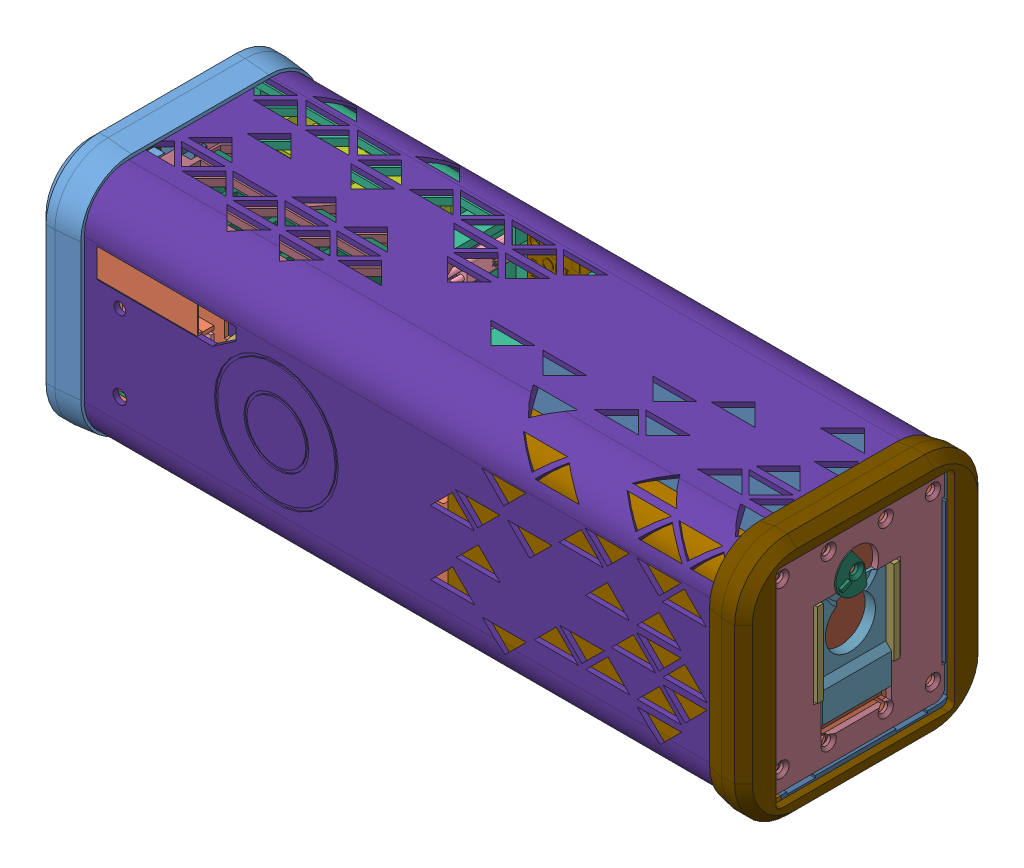
SolidWorks assembly Full Powerbank Assembly, configuration Default. Lengths in mm.
Overall size (243.88 83.1 83.1).
73 component instances, 40 part files, 193 mates.
Components (placement in the parent):
- Battery Holder base part-1: Battery Holder base part [Default] at (46.0757 75.848 60.5511) size (105.5 58.5 60)
- 18650 battery-1: 18650 battery [Default] at (37.7028 85.7801 99.4336) x (0 -1 0) z (0.549149 0 -0.835725) size (65 18 18)
- 18650 battery-2: 18650 battery [Default] at (74.8709 17.9159 53.2312) x (0 1 0) z (-0.546944 0 0.837169) size (65 18 18)
- 18650 battery-3: 18650 battery [Default] at (54.8709 17.9159 53.2312) x (0 1 0) z (-0.546944 0 0.837169) size (65 18 18)
- 18650 battery-4: 18650 battery [Default] at (34.8709 17.9159 53.2312) x (0 1 0) z (-0.546944 0 0.837169) size (65 18 18)
- 18650 battery-5: 18650 battery [Default] at (46.8938 85.7801 64.9021) x (0 -1 0) z (0 0 1) size (65 18 18)
- 18650 battery-6: 18650 battery [Default] at (82.8706 85.7801 62.4579) x (0 -1 0) z (-0.77356 0 0.633723) size (65 18 18)
- 18650 battery-7: 18650 battery [Default] at (86.8938 85.7801 64.9021) x (0 -1 0) z (0 0 1) size (65 18 18)
- 18650 battery-8: 18650 battery [Default] at (38.5972 85.7801 39.7291) x (0 -1 0) z (0.803541 0 0.595249) size (65 18 18)
- 18650 battery-9: 18650 battery [Default] at (86.8938 85.7801 24.9021) x (0 -1 0) z (0 0 1) size (65 18 18)
- 18650 battery-10: 18650 battery [Default] at (114.8709 17.9159 53.2312) x (0 1 0) z (-0.546944 0 0.837169) size (65 18 18)
- 18650 battery-11: 18650 battery [Default] at (6.8938 85.7801 24.9021) x (0 -1 0) z (0 0 1) size (65 18 18)
- 18650 battery-12: 18650 battery [Default] at (94.8709 17.9159 53.2312) x (0 1 0) z (-0.546944 0 0.837169) size (65 18 18)
- 18650 battery-13: 18650 battery [Default] at (26.8938 85.7801 24.9021) x (0 -1 0) z (0 0 1) size (65 18 18)
- 18650 battery-14: 18650 battery [Default] at (6.8938 85.7801 64.9021) x (0 -1 0) z (0 0 1) size (65 18 18)
- 18650 battery-15: 18650 battery [Default] at (66.8938 85.7801 24.9021) x (0 -1 0) z (0 0 1) size (65 18 18)
- Battery Holder Top Cap-2: Battery Holder Top Cap [Default] at (46.0757 27.848 60.5511) x (1 0 0) z (0 0 -1) size (119 13.21 60)
- Battery Holder Top Cap-3: Battery Holder Top Cap [Default] at (46.0757 27.848 60.5511) x (1 0 0) z (0 0 -1) size (119 13.21 60)
- 3s 25A BMS with balance-1: 3s 25A BMS with balance [Default] at (7.4633 51.471 58.769) x (0 -1 0) z (0 0 -1) size (56 3.6 45)
- XT60 male-2: XT60 male [Default] at (-1.7367 23.848 60.4011) x (0 0 1) z (-1 0 0) size (15.6 8 21.8)
- Electronics body-1: Electronics body [Default] at (-116.5367 53.3713 61.8287) x (0 0 1) z (0 1 0) size (63.75 130 74.25)
- 12V 150W inverter-1: 12V 150W inverter [Default] at (-62.0893 52.4138 28.0511) x (0 -1 0) z (-1 0 0) size (60 23.7 68)
- 20A relay-1: 20A relay [Default] at (-39.9404 68.2419 39.7511) x (0 1 0) z (-1 0 0) size (15.8 17.9 12.2)
- Step down converter Constant current-3: Step down converter Constant current [Default] at (-9.196 56.3158 28.5511) x (1 0 0) z (0 -1 0) size (26.3 16.25 62)
- 20A relay-2: 20A relay [Default] at (-34.6303 50.9419 39.7511) x (0 1 0) z (-1 0 0) size (15.8 17.9 12.2)
- 20A relay-3: 20A relay [Default] at (-34.6303 35.0419 39.7511) x (0 1 0) z (-1 0 0) size (15.8 17.9 12.2)
- DC Jack-1: DC Jack [Default] at (-116.5367 23.0836 36.7169) x (0 -1 0) z (0 0 1) size (9 15 15)
- USB C Female-1: USB C Female [Default] at (-108.5138 21.548 52.9665) x (0 0 1) z (-1 0 0) size (15 3.2 17.4)
- XT60 female-2: XT60 female [Default] at (-26.4367 23.848 60.2511) x (0 0 1) z (1 0 0) size (15.6 8 21.4)
- Electronics body mid layer-1: Electronics body mid layer [Default] at (-53.3688 57.1686 58.5511) x (1 0 0) z (0 -1 0) size (118 34.5 67.32)
- DC Jack-2: DC Jack [Default] at (-116.5367 78.5138 64.8993) x (0 0 1) z (0 1 0) size (9 15 15)
- Switch-2: Switch [Default] at (-110.0367 53.122 67.0755) x (0 0 1) z (0 -1 0) size (13 15.27 7)
- 200W boost converter 10A-4: 200W boost converter 10A [Default] at (-65.093 72.5468 63.0511) x (0 1 0) z (1 0 0) size (36.5 22.7 70)
- 20A relay-4: 20A relay [Default] at (-39.1428 41.3517 74.7511) x (1 0 0) z (0 1 0) size (15.8 17.9 12.2)
- 60x10mm fan-1: 60x10mm fan [Default] at (-62.9534 14.848 38.0511) size (60 10 60)
- Switch-3: Switch [Default] at (-110.0367 53.122 80.0755) x (0 0 1) z (0 -1 0) size (13 15.27 7)
- 12V to 5V USB-3: 12V to 5V USB [Default] at (-97.3792 41.0946 68.5511) x (0 -1 0) z (-1 0 0) size (28 15 58.9)
- Voltmeter and switch brcket-1: Voltmeter and switch brcket [Default] at (-110.5367 72.2443 73.8058) x (0 -1 0) z (0 0 -1) size (24.51 6 20.36)
- Voltmeter-2: Voltmeter [Default] at (-107.6767 73.0795 74.7637) x (0 -1 0) z (0 0 -1) size (22.8 8.96 10.5)
- Switch-4: Switch [Default] at (-110.0367 75.6225 88.1876) x (0 1 0) z (0 0 1) size (13 15.27 7)
- Electronics body top layer-4: Electronics body top layer [Default] at (13.4633 30.4962 89.1111) x (0 0 -1) z (0 1 0) size (14.91 130 73.98)
- Wireless charging coil-1: Wireless charging coil [Default] at (-43.0367 51.348 94.5511) x (0.923141 0.384463 0) z (0.384463 -0.923141 0) size (50 2.5 50)
- Wireless charging circuit-1: Wireless charging circuit [Default] at (-87.044 48.0841 93.5511) x (1 0 0) z (0 -1 0) size (30 2.5 32)
- Switch-6: Switch [Default] at (-110.0367 32.822 90.5755) x (0 0 1) z (0 -1 0) size (13 15.27 7)
- Switch-7: Switch [Default] at (-110.0367 25.822 90.5755) x (0 0 1) z (0 -1 0) size (13 15.27 7)
- AC Socket-2: AC Socket [Default] at (-119.5367 49.2567 56.8454) x (0 1 0) z (0 0 1) size (26.7 23.5 26.7)
- Adj bracket-2: Adj bracket [Default] at (-111.5367 61.6916 49.3943) x (0 1 0) z (0 0 1) size (26 10 6.2)
- Potencometer-2: Potencometer [Default] at (-109.2352 70.848 59.2044) x (-1 0 0) z (0 0 1) size (10 5 11.5)
- Adj Knob-1: Adj Knob [Default] at (-114.0367 68.148 56.9511) x (0.827198 -0.56191 0) z (0.56191 0.827198 0) size (25.5 4.9 16.38)
- Battery compartment base-1: Battery compartment base [Default] at (13.4633 48.4447 41.738) x (0 0 -1) z (0 -1 0) size (10.5 108.5 73.98)
- Battery compartment Top - Copy-1: Battery compartment Top - Copy [Default] at (13.4633 48.4447 41.738) x (0 0 -1) z (0 -1 0) size (63.5 108.3 74)
- Battery locking mechnism base-1: Battery locking mechnism base [Default] at (107.4633 55.2514 60.4566) x (0 0 1) z (0 1 0) size (60 5.5 69)
- Locking Shim-1: Locking Shim [Default] at (109.4633 53.6697 81.7455) x (0 0 -1) z (0 -1 0) size (25 6.1 28.5)
- Locking Shim-2: Locking Shim [Default] at (109.4633 50.0263 39.3567) x (0 0 1) z (0 1 0) size (25 6.1 28.5)
- Locking mechnism lid-1: Locking mechnism lid [Default] at (112.9633 51.742 60.2444) x (0 0 -1) z (0 -1 0) size (60 2 69)
- Pull Tab-1: Pull Tab [Default] at (109.4633 54.1884 58.8467) x (0 0 -1) z (0 -1 0) size (23.5 5.5 35.5)
- Rotate lock-1: Rotate lock [Default] at (112.9633 69.3177 62.7085) x (0 0.929004 0.37007) z (0 0.37007 -0.929004) size (14 3 9.86)
- Voltmeter-6: Voltmeter [Default] at (-107.6767 49.0795 88.9532) x (0 -1 0) z (0 0 -1) size (22.8 8.96 10.5)
- Switch-8: Switch [Default] at (-110.0367 60.322 40.0755) x (0 0 1) z (0 -1 0) size (13 15.27 7)
- IO shield-2: IO shield [Default] at (-116.5367 48.4447 41.738) x (0 0 -1) z (1 0 0) size (74 74 2.42)
- Outer sleeve-2: Outer sleeve [Default] at (-118.7367 53.1256 59.0279) x (0 1 0) z (1 0 0) size (78.6 78.6 234.7)
- Bottom Cap-1: Bottom Cap [Default] at (117.9633 58.0602 59.1604) x (0 1 0) z (0 0 1) size (82.6 12.5 82.6)
- Top Cap-1: Top Cap [Default] at (-120.7367 47.972 56.9587) x (0 -1 0) z (0 0 1) size (82.6 14 82.6)
- RGB controller cover-1: RGB controller cover [Default] at (-91.5447 69.6442 99.8511) x (1 0 0) z (0 1 0) size (34 1.65 9.5)
- AC Socket-3: AC Socket [Default] at (-118.7367 48.6742 56.9592) x (0 1 0) z (0 0 1) size (26.7 23.5 26.7)
- Inscription-1: Inscription [Default] at (78.4734 13.348 37.1232) x (1 0 0) z (0 0 -1) size (59.5 0.8 19.5)
- Temperature switch-1: Temperature switch [Default] at (-66.4617 65.07 90.1327) x (0 0 1) z (0 -1 0) size (7.5 3.65 24.95)
- Temperature switch-2: Temperature switch [Default] at (13.7133 34.6858 27.1511) x (0 -1 0) z (-1 0 0) size (7.5 3.65 24.95)
- Temperature switch-3: Temperature switch [Default] at (-36.5367 57.6858 44.8011) x (0 -1 0) z (0 0 1) size (7.5 3.65 24.95)
- Temperature switch-4: Temperature switch [Default] at (-74.9745 43.9916 68.5511) x (1 0 0) z (0 1 0) size (7.5 3.65 24.95)
- Temperature switch-5: Temperature switch [Default] at (-67.826 47.8234 58.5511) x (0 -1 0) z (1 0 0) size (7.5 3.65 24.95)
- Temperature switch-6: Temperature switch [Default] at (-79.935 28.848 59.2037) x (0 0 1) z (-1 0 0) size (7.5 3.65 24.95)
- Temperature switch-7: Temperature switch [Default] at (13.7133 68.5103 93.9511) x (0 1 0) z (-1 0 0) size (7.5 3.65 24.95)
Mates (geometry in assembly coordinates):
- Concentric1: concentric: cylinder of Battery Holder base part-1 through (17.4633 85.848 80.5511) axis (0 -1 0) radius 9.5; cylinder of 18650 battery-14 through (17.4633 91.7511 80.5511) axis (0 1 0) radius 9
- Coincident7: coincident: plane of Battery Holder base part-1 through (46.0757 84.348 60.5511) normal (0 -1 0); plane of 18650 battery-14 through (24.5633 84.348 80.5511) normal (0 1 0)
- Concentric2: concentric: cylinder of Battery Holder base part-1 through (37.4633 85.848 80.5511) axis (0 -1 0) radius 9.5; cylinder of 18650 battery-1 through (37.4633 91.7511 80.5511) axis (0 1 0) radius 9
- Coincident8: coincident: plane of Battery Holder base part-1 through (46.0757 84.348 60.5511) normal (0 -1 0); plane of 18650 battery-1 through (31.5296 84.348 76.6522) normal (0 1 0)
- Concentric3: concentric: cylinder of Battery Holder base part-1 through (57.4633 85.848 80.5511) axis (0 -1 0) radius 9.5; cylinder of 18650 battery-5 through (57.4633 91.7511 80.5511) axis (0 1 0) radius 9
- Coincident9: coincident: plane of Battery Holder base part-1 through (46.0757 84.348 60.5511) normal (0 -1 0); plane of 18650 battery-5 through (64.5633 84.348 80.5511) normal (0 1 0)
- Concentric4: concentric: cylinder of Battery Holder base part-1 through (77.4633 85.848 80.5511) axis (0 -1 0) radius 9.5; cylinder of 18650 battery-6 through (77.4633 91.7511 80.5511) axis (0 1 0) radius 9
- Coincident10: coincident: plane of Battery Holder base part-1 through (46.0757 84.348 60.5511) normal (0 -1 0); plane of 18650 battery-6 through (81.9627 84.348 86.0434) normal (0 1 0)
- Concentric5: concentric: cylinder of Battery Holder base part-1 through (97.4633 85.848 80.5511) axis (0 -1 0) radius 9.5; cylinder of 18650 battery-7 through (97.4633 91.7511 80.5511) axis (0 1 0) radius 9
- Coincident11: coincident: plane of Battery Holder base part-1 through (46.0757 84.348 60.5511) normal (0 -1 0); plane of 18650 battery-7 through (104.5633 84.348 80.5511) normal (0 1 0)
- Concentric6: concentric: cylinder of Battery Holder base part-1 through (17.4633 85.848 60.5511) axis (0 -1 0) radius 9.5; cylinder of 18650 battery-4 through (17.4633 11.9449 60.5511) axis (0 -1 0) radius 9
- Coincident12: coincident: plane of Battery Holder base part-1 through (46.0757 84.348 60.5511) normal (0 -1 0); plane of 18650 battery-4 through (9.9288 84.348 55.6286) normal (0 1 0)
- Concentric7: concentric: cylinder of Battery Holder base part-1 through (37.4633 85.848 60.5511) axis (0 -1 0) radius 9.5; cylinder of 18650 battery-3 through (37.4633 11.9449 60.5511) axis (0 -1 0) radius 9
- Coincident13: coincident: plane of Battery Holder base part-1 through (46.0757 84.348 60.5511) normal (0 -1 0); plane of 18650 battery-3 through (29.9288 84.348 55.6286) normal (0 1 0)
- Concentric8: concentric: cylinder of Battery Holder base part-1 through (57.4633 85.848 60.5511) axis (0 -1 0) radius 9.5; cylinder of 18650 battery-2 through (57.4633 11.9449 60.5511) axis (0 -1 0) radius 9
- Coincident14: coincident: plane of Battery Holder base part-1 through (46.0757 84.348 60.5511) normal (0 -1 0); plane of 18650 battery-2 through (49.9288 84.348 55.6286) normal (0 1 0)
- Concentric9: concentric: cylinder of Battery Holder base part-1 through (77.4633 85.848 60.5511) axis (0 -1 0) radius 9.5; cylinder of 18650 battery-12 through (77.4633 11.9449 60.5511) axis (0 -1 0) radius 9
- Coincident15: coincident: plane of Battery Holder base part-1 through (46.0757 84.348 60.5511) normal (0 -1 0); plane of 18650 battery-12 through (69.9288 84.348 55.6286) normal (0 1 0)
- Concentric10: concentric: cylinder of Battery Holder base part-1 through (97.4633 85.848 60.5511) axis (0 -1 0) radius 9.5; cylinder of 18650 battery-10 through (97.4633 11.9449 60.5511) axis (0 -1 0) radius 9
- Coincident16: coincident: plane of Battery Holder base part-1 through (46.0757 84.348 60.5511) normal (0 -1 0); plane of 18650 battery-10 through (89.9288 84.348 55.6286) normal (0 1 0)
- Concentric11: concentric: cylinder of Battery Holder base part-1 through (37.4633 85.848 40.5511) axis (0 -1 0) radius 9.5; cylinder of 18650 battery-13 through (37.4633 91.7511 40.5511) axis (0 1 0) radius 9
- Coincident17: coincident: plane of Battery Holder base part-1 through (46.0757 84.348 60.5511) normal (0 -1 0); plane of 18650 battery-13 through (44.5633 84.348 40.5511) normal (0 1 0)
- Concentric12: concentric: cylinder of Battery Holder base part-1 through (17.4633 85.848 40.5511) axis (0 -1 0) radius 9.5; cylinder of 18650 battery-11 through (17.4633 91.7511 40.5511) axis (0 1 0) radius 9
- Coincident18: coincident: plane of Battery Holder base part-1 through (46.0757 84.348 60.5511) normal (0 -1 0); plane of 18650 battery-11 through (24.5633 84.348 40.5511) normal (0 1 0)
- Concentric13: concentric: cylinder of Battery Holder base part-1 through (57.4633 85.848 40.5511) axis (0 -1 0) radius 9.5; cylinder of 18650 battery-8 through (57.4633 91.7511 40.5511) axis (0 1 0) radius 9
- Coincident19: coincident: plane of Battery Holder base part-1 through (46.0757 84.348 60.5511) normal (0 -1 0); plane of 18650 battery-8 through (61.6896 84.348 34.846) normal (0 1 0)
- Concentric14: concentric: cylinder of Battery Holder base part-1 through (77.4633 85.848 40.5511) axis (0 -1 0) radius 9.5; cylinder of 18650 battery-15 through (77.4633 91.7511 40.5511) axis (0 1 0) radius 9
- Coincident20: coincident: plane of Battery Holder base part-1 through (46.0757 84.348 60.5511) normal (0 -1 0); plane of 18650 battery-15 through (84.5633 84.348 40.5511) normal (0 1 0)
- Concentric15: concentric: cylinder of Battery Holder base part-1 through (97.4633 85.848 40.5511) axis (0 -1 0) radius 9.5; cylinder of 18650 battery-9 through (97.4633 91.7511 40.5511) axis (0 1 0) radius 9
- Coincident21: coincident: plane of Battery Holder base part-1 through (46.0757 84.348 60.5511) normal (0 -1 0); plane of 18650 battery-9 through (104.5633 84.348 40.5511) normal (0 1 0)
- Coincident22: coincident: plane of 18650 battery-4 through (11.5194 19.348 56.6678) normal (0 -1 0); plane of Battery Holder Top Cap-2 through (46.0757 19.348 60.5511) normal (0 1 0)
- Coincident23: coincident: plane of Battery Holder base part-1 through (46.0757 85.848 90.5511) normal (0 0 1); plane of Battery Holder Top Cap-2 through (46.0757 17.848 90.5511) normal (0 0 1)
- Coincident24: coincident: plane of Battery Holder base part-1 through (7.4633 85.848 60.5511) normal (-1 0 0); plane of Battery Holder Top Cap-2 through (7.4633 17.848 60.5511) normal (-1 0 0)
- Coincident25: coincident: plane of 18650 battery-4 through (11.5194 19.348 56.6678) normal (0 -1 0); plane of Battery Holder Top Cap-3 through (46.0757 19.348 60.5511) normal (0 1 0)
- Coincident26: coincident: plane of Battery Holder base part-1 through (46.0757 85.848 30.5511) normal (0 0 -1); plane of Battery Holder Top Cap-3 through (46.0757 17.848 30.5511) normal (0 0 -1)
- Coincident27: coincident: plane of Battery Holder base part-1 through (7.4633 85.848 60.5511) normal (-1 0 0); plane of Battery Holder Top Cap-3 through (7.4633 17.848 60.5511) normal (-1 0 0)
- Coincident28: coincident: plane of Battery Holder base part-1 through (7.4633 85.848 60.5511) normal (-1 0 0); plane of 3s 25A BMS with balance-1 through (7.4633 51.471 58.769) normal (1 0 0)
- Distance1: distance = 7 mm: plane of 3s 25A BMS with balance-1 through (6.2633 84.348 37.5511) normal (0 0 -1); plane of Battery Holder base part-1 through (46.0757 85.848 30.5511) normal (0 0 -1)
- Coincident37: coincident: plane of Battery Holder Top Cap-3 through (17.6713 17.348 52.6011) normal (0 0 1); plane of XT60 male-2 through (-1.7367 25.248 52.6011) normal (0 0 -1)
- Coincident38: coincident: plane of Battery Holder Top Cap-3 through (-9.5367 27.848 60.5511) normal (-1 0 0); plane of XT60 male-2 through (-9.5367 23.848 61.0461) normal (-1 0 0)
- Coincident39: coincident: plane of Battery Holder Top Cap-3 through (-2.5367 19.848 70.5511) normal (0 1 0); plane of XT60 male-2 through (-1.7367 19.848 55.6011) normal (0 -1 0)
- Coincident43: coincident: plane of Electronics body-1 through (-48.5367 24.848 61.8287) normal (0 1 0); plane of 12V 150W inverter-1 through (-48.5367 24.848 29.7511) normal (0 -1 0)
- Coincident44: coincident: plane of Electronics body-1 through (-48.5367 53.3713 28.0511) normal (0 0 1); plane of 12V 150W inverter-1 through (-62.0893 52.4138 28.0511) normal (0 0 -1)
- Coincident45: coincident: plane of Electronics body-1 through (-116.5367 77.848 34.5511) normal (-1 0 0); plane of 12V 150W inverter-1 through (-116.5367 84.848 29.7511) normal (-1 0 0)
- Coincident60: coincident: plane of Electronics body-1 through (-16.5367 25.348 26.0511) normal (0 0 1); plane of 20A relay-1 through (-39.9404 68.2419 26.0511) normal (0 0 -1)
- Coincident61: coincident: plane of Electronics body-1 through (-36.5367 53.3713 35.0511) normal (-1 0 0); plane of 20A relay-1 through (-36.5367 78.348 26.0511) normal (1 0 0)
- Coincident62: coincident: plane of Electronics body-1 through (-116.5367 78.348 35.0511) normal (0 -1 0); plane of 20A relay-1 through (-48.7367 78.348 26.0511) normal (0 1 0)
- Parallel11: parallel: plane of Battery Holder Top Cap-3 through (46.0757 17.848 30.5511) normal (0 0 -1); plane of Electronics body-1 through (-16.5367 25.348 26.0511) normal (0 0 1)
- Coincident70: coincident: plane of Electronics body-1 through (-3.2367 81.348 28.5511) normal (0 0 1); plane of Step down converter Constant current-3 through (-9.196 56.3158 28.5511) normal (0 0 -1)
- Concentric16: concentric: cylinder of Electronics body-1 through (-3.2367 81.348 10.0511) axis (0 0 1) radius 1.35; cylinder of Step down converter Constant current-3 through (-3.2367 81.348 30.1511) axis (0 0 -1) radius 1.675
- Concentric17: concentric: cylinder of Electronics body-1 through (-24.5367 24.348 10.0511) axis (0 0 1) radius 1.35; cylinder of Step down converter Constant current-3 through (-24.5367 24.348 30.1511) axis (0 0 -1) radius 1.675
- Coincident71: coincident: plane of Electronics body-1 through (-16.5367 25.348 26.0511) normal (0 0 1); plane of 20A relay-2 through (-34.6303 50.9419 26.0511) normal (0 0 -1)
- Coincident72: coincident: plane of Electronics body-1 through (-43.4266 61.048 72.8942) normal (1 0 0); plane of 20A relay-2 through (-43.4266 61.048 26.0511) normal (-1 0 0)
- Coincident73: coincident: plane of Electronics body-1 through (-116.5367 61.048 35.0511) normal (0 -1 0); plane of 20A relay-2 through (-43.4266 61.048 26.0511) normal (0 1 0)
- Coincident74: coincident: plane of Electronics body-1 through (-16.5367 25.348 26.0511) normal (0 0 1); plane of 20A relay-3 through (-34.6303 35.0419 26.0511) normal (0 0 -1)
- Coincident75: coincident: plane of Electronics body-1 through (-43.4266 61.048 72.8942) normal (1 0 0); plane of 20A relay-3 through (-43.4266 45.148 26.0511) normal (-1 0 0)
- Coincident76: coincident: plane of Electronics body-1 through (-43.4266 29.348 72.8942) normal (0 1 0); plane of 20A relay-3 through (-43.4266 29.348 26.0511) normal (0 -1 0)
- Coincident77: coincident: plane of Electronics body-1 through (-48.5367 53.3713 31.0511) normal (0 0 1); plane of DC Jack-1 through (-101.5367 26.9318 31.0511) normal (0 0 -1)
- Coincident78: coincident: plane of Electronics body-1 through (-102.5367 17.9318 31.0511) normal (0 1 0); plane of DC Jack-1 through (-101.5367 17.9318 31.0511) normal (0 -1 0)
- Coincident79: coincident: plane of Electronics body-1 through (-116.5367 77.848 34.5511) normal (-1 0 0); plane of DC Jack-1 through (-116.5367 23.0836 36.7169) normal (-1 0 0)
- Coincident80: coincident: plane of Electronics body-1 through (-108.0367 20.348 61.8287) normal (0 1 0); plane of USB C Female-1 through (-107.4367 20.348 50.0221) normal (0 -1 0)
- Coincident81: coincident: plane of Electronics body-1 through (-108.0367 53.3713 45.8338) normal (0 0 1); plane of USB C Female-1 through (-100.8367 22.348 45.8338) normal (0 0 -1)
- Coincident82: coincident: plane of Electronics body-1 through (-116.5367 77.848 34.5511) normal (-1 0 0); plane of USB C Female-1 through (-116.5367 22.348 45.8338) normal (-1 0 0)
- Coincident83: coincident: plane of Battery Holder base part-1 through (17.4633 86.348 60.5511) normal (0 1 0); plane of Electronics body-1 through (-16.5367 86.348 34.0511) normal (0 -1 0)
- Distance6: distance = 4.5 mm: plane of Battery Holder base part-1 through (46.0757 85.848 30.5511) normal (0 0 -1); plane of Electronics body-1 through (-16.5367 25.348 26.0511) normal (0 0 1)
- Coincident89: coincident: plane of Electronics body-1 through (-116.5367 27.348 52.4511) normal (0 0 1); plane of XT60 female-2 through (-26.4367 22.448 52.4511) normal (0 0 -1)
- Coincident91: coincident: plane of Electronics body-1 through (-116.5367 19.848 61.8287) normal (0 1 0); plane of XT60 female-2 through (-26.4367 19.848 68.0511) normal (0 -1 0)
- Coincident92: coincident: plane of Electronics body-1 through (-116.5367 27.348 52.4511) normal (0 0 1); plane of XT60 female-2 through (-26.4367 22.448 52.4511) normal (0 0 -1)
- Coincident93: coincident: plane of Electronics body-1 through (-10.0367 19.848 61.8287) normal (1 0 0); plane of XT60 female-2 through (-10.0367 23.848 60.8961) normal (1 0 0)
- Coincident99: coincident: plane of Electronics body-1 through (67.563 100.6452 58.5511) normal (0 0 1); plane of Electronics body mid layer-1 through (-53.3688 57.1686 58.5511) normal (0 0 -1)
- Coincident100: coincident: plane of Electronics body-1 through (-116.5367 77.848 34.5511) normal (-1 0 0); plane of Electronics body mid layer-1 through (-116.5367 88.848 61.0511) normal (-1 0 0)
- Coincident101: coincident: plane of Electronics body-1 through (-16.5367 88.848 34.5511) normal (0 1 0); plane of Electronics body mid layer-1 through (-116.5367 88.848 61.0511) normal (0 1 0)
- Coincident107: coincident: plane of Electronics body mid layer-1 through (-53.3688 57.1686 61.0511) normal (0 0 1); plane of DC Jack-2 through (-101.5367 72.848 61.0511) normal (0 0 -1)
- Coincident108: coincident: plane of Electronics body mid layer-1 through (-53.3688 72.848 71.0511) normal (0 1 0); plane of DC Jack-2 through (-101.5367 72.848 61.0511) normal (0 -1 0)
- Coincident109: coincident: plane of Electronics body mid layer-1 through (-116.5367 88.848 61.0511) normal (-1 0 0); plane of DC Jack-2 through (-116.5367 78.5138 64.8993) normal (-1 0 0)
- LimitDistance1: limit distance = 0.5 mm: plane of Battery Holder Top Cap-3 through (-9.5367 27.848 60.5511) normal (-1 0 0); plane of Electronics body-1 through (-10.0367 19.848 61.8287) normal (1 0 0)
- Coincident113: coincident: plane of Electronics body mid layer-1 through (-53.3688 57.1686 61.0511) normal (0 0 1); plane of Switch-2 through (-116.4367 58.548 61.0511) normal (0 0 -1)
- Coincident114: coincident: plane of Electronics body mid layer-1 through (-110.5367 51.648 59.908) normal (0 1 0); plane of Switch-2 through (-110.0367 51.648 67.0755) normal (0 -1 0)
- Coincident115: coincident: plane of Electronics body mid layer-1 through (-116.5367 88.848 61.0511) normal (-1 0 0); plane of Switch-2 through (-116.5367 53.122 67.0755) normal (-1 0 0)
- Coincident119: coincident: plane of Electronics body mid layer-1 through (-53.3688 57.1686 63.0511) normal (0 0 1); plane of 200W boost converter 10A-4 through (-65.093 72.5468 63.0511) normal (0 0 -1)
- Coincident120: coincident: plane of Electronics body mid layer-1 through (-29.0367 51.148 64.8511) normal (0 1 0); plane of 200W boost converter 10A-4 through (-99.5367 51.148 64.7511) normal (0 -1 0)
- Coincident122: coincident: plane of Electronics body mid layer-1 through (-53.3688 57.1686 61.0511) normal (0 0 1); plane of 20A relay-4 through (-39.1428 41.3517 61.0511) normal (0 0 -1)
- Coincident123: coincident: plane of Electronics body mid layer-1 through (-44.7367 37.948 69.0511) normal (0 1 0); plane of 20A relay-4 through (-29.0367 37.948 61.0511) normal (0 -1 0)
- Coincident124: coincident: plane of Electronics body mid layer-1 through (-29.0367 50.148 69.0511) normal (-1 0 0); plane of 20A relay-4 through (-29.0367 50.148 61.0511) normal (1 0 0)
- Coincident125: coincident: plane of Electronics body-1 through (-96.5367 37.848 91.0511) normal (1 0 0); plane of 60x10mm fan-1 through (-96.5367 24.848 31.0511) normal (-1 0 0)
- Coincident126: coincident: plane of Electronics body-1 through (-36.5367 37.848 31.0511) normal (0 0 1); plane of 60x10mm fan-1 through (-96.5367 24.848 31.0511) normal (0 0 -1)
- Coincident127: coincident: plane of Electronics body-1 through (-16.5367 14.848 34.5511) normal (0 -1 0); plane of 60x10mm fan-1 through (-62.9534 14.848 38.0511) normal (0 -1 0)
- Coincident128: coincident: plane of Switch-2 through (-116.4367 58.548 74.0511) normal (0 0 1); plane of Switch-3 through (-116.4367 58.548 74.0511) normal (0 0 -1)
- Coincident129: coincident: plane of Electronics body mid layer-1 through (-110.5367 51.648 59.908) normal (0 1 0); plane of Switch-3 through (-110.0367 51.648 80.0755) normal (0 -1 0)
- Coincident130: coincident: plane of Electronics body mid layer-1 through (-116.5367 88.848 61.0511) normal (-1 0 0); plane of Switch-3 through (-116.5367 53.122 80.0755) normal (-1 0 0)
- Coincident131: coincident: plane of Electronics body mid layer-1 through (-53.3688 57.1686 68.5511) normal (0 0 1); plane of 12V to 5V USB-3 through (-97.3792 41.0946 68.5511) normal (0 0 -1)
- Coincident132: coincident: plane of Electronics body mid layer-1 through (-105.511 53.2416 69.7511) normal (0 -1 0); plane of 12V to 5V USB-3 through (-97.3792 53.2416 69.5511) normal (0 1 0)
- Coincident133: coincident: plane of Electronics body-1 through (-116.5367 77.848 34.5511) normal (-1 0 0); plane of 12V to 5V USB-3 through (-116.5367 46.4916 64.5511) normal (-1 0 0)
- Coincident139: coincident: plane of Electronics body mid layer-1 through (-116.5367 88.848 61.0511) normal (-1 0 0); plane of Voltmeter and switch brcket-1 through (-116.5367 72.2443 73.8058) normal (-1 0 0)
- Coincident140: coincident: plane of Electronics body mid layer-1 through (-53.3688 63.848 71.0511) normal (0 -1 0); plane of Voltmeter and switch brcket-1 through (-116.5367 63.848 84.1616) normal (0 -1 0)
- Coincident141: coincident: plane of Voltmeter and switch brcket-1 through (-116.5367 87.848 72.6616) normal (0 0 1); plane of Voltmeter-2 through (-116.5367 87.148 72.6616) normal (0 0 -1)
- Coincident142: coincident: plane of Voltmeter and switch brcket-1 through (-116.5367 72.2443 73.8058) normal (-1 0 0); plane of Voltmeter-2 through (-116.5367 73.0795 74.7637) normal (-1 0 0)
- Coincident143: coincident: plane of Voltmeter and switch brcket-1 through (-116.5367 64.348 72.6616) normal (0 1 0); plane of Voltmeter-2 through (-116.5367 64.348 72.6616) normal (0 -1 0)
- Coincident144: coincident: plane of Voltmeter and switch brcket-1 through (-92.969 69.598 73.8058) normal (0 1 0); plane of Switch-4 through (-116.4367 69.598 82.7616) normal (0 -1 0)
- Coincident145: coincident: plane of Voltmeter and switch brcket-1 through (-92.969 72.2443 89.6616) normal (0 0 -1); plane of Switch-4 through (-110.0367 75.6225 89.6616) normal (0 0 1)
- Coincident146: coincident: plane of Voltmeter and switch brcket-1 through (-116.5367 72.2443 73.8058) normal (-1 0 0); plane of Switch-4 through (-116.5367 75.6225 88.1876) normal (-1 0 0)
- Coincident147: coincident: plane of Electronics body mid layer-1 through (-99.5367 88.848 63.0511) normal (-1 0 0); plane of 200W boost converter 10A-4 through (-99.5367 51.148 64.7511) normal (-1 0 0)
- Coincident156: coincident: circle of Electronics body-1; plane of Electronics body top layer-4 through (-116.5367 77.848 86.5511) normal (-1 0 0)
- Coincident157: coincident: plane of Electronics body-1 through (-116.5367 53.3713 87.0511) normal (0 0 1); plane of Electronics body top layer-4 through (13.4633 30.4962 87.0511) normal (0 0 -1)
- Coincident158: coincident: line of Electronics body-1 through (13.4633 14.8594 87.0511) axis (-1 0 0); line of Electronics body top layer-4 through (13.4633 14.8594 87.0511) axis (-1 0 0)
- Concentric18: concentric: cylinder of Electronics body top layer-4 through (-43.0367 51.348 94.5511) axis (0 0 -1) radius 25.5; cylinder of Wireless charging coil-1 through (-43.0367 51.348 95.5511) axis (0 0 -1) radius 25
- Coincident159: coincident: plane of Electronics body top layer-4 through (-43.0367 51.348 94.5511) normal (0 0 1); plane of Wireless charging coil-1 through (-43.0367 51.348 94.5511) normal (0 0 -1)
- Coincident160: coincident: plane of Electronics body top layer-4 through (-86.5367 30.4962 93.5511) normal (0 0 1); plane of Wireless charging circuit-1 through (-94.0367 37.348 93.5511) normal (0 0 -1)
- Coincident178: coincident: plane of Electronics body top layer-4 through (-110.5367 30.4962 84.5511) normal (0 0 1); plane of Switch-7 through (-116.4367 31.248 84.5511) normal (0 0 -1)
- Coincident179: coincident: plane of Electronics body top layer-4 through (-110.5367 24.348 89.1111) normal (0 1 0); plane of Switch-7 through (-110.0367 24.348 90.5755) normal (0 -1 0)
- Coincident180: coincident: plane of Electronics body top layer-4 through (-116.5367 77.848 86.5511) normal (-1 0 0); plane of Switch-7 through (-116.5367 25.822 90.5755) normal (-1 0 0)
- Coincident181: coincident: plane of Electronics body top layer-4 through (-110.5367 30.4962 84.5511) normal (0 0 1); plane of Switch-6 through (-116.4367 38.248 84.5511) normal (0 0 -1)
- Coincident183: coincident: plane of Electronics body top layer-4 through (-107.5367 38.348 89.1111) normal (0 -1 0); plane of Switch-6 through (-110.0367 38.348 90.5755) normal (0 1 0)
- Coincident184: coincident: plane of Electronics body top layer-4 through (-116.5367 77.848 86.5511) normal (-1 0 0); plane of Switch-6 through (-116.5367 32.822 90.5755) normal (-1 0 0)
- Distance16: distance = 3 mm: plane of Electronics body-1 through (-116.5367 77.848 34.5511) normal (-1 0 0); plane of AC Socket-2 through (-119.5367 49.2567 56.8454) normal (1 0 0)
- Coincident187: coincident: plane of Electronics body top layer-4 through (-97.1514 31.348 97.5511) normal (0 1 0); plane of Wireless charging circuit-1 through (-94.0367 31.348 94.5511) normal (0 -1 0)
- Coincident188: coincident: plane of Electronics body top layer-4 through (-70.0367 31.348 97.5511) normal (1 0 0); plane of Wireless charging circuit-1 through (-70.0367 63.348 94.5511) normal (1 0 0)
- Coincident192: coincident: plane of Electronics body mid layer-1 through (-116.5367 88.848 61.0511) normal (-1 0 0); plane of Adj bracket-2 through (-116.5367 61.6916 49.3943) normal (-1 0 0)
- Coincident195: coincident: plane of Electronics body mid layer-1 through (-104.5367 57.1686 58.5511) normal (-1 0 0); plane of Potencometer-2 through (-104.5367 65.848 58.5511) normal (1 0 0)
- Coincident196: coincident: plane of Electronics body mid layer-1 through (-53.3688 65.848 71.0511) normal (0 1 0); plane of Potencometer-2 through (-109.2352 65.848 59.2044) normal (0 -1 0)
- Coincident197: coincident: plane of Electronics body mid layer-1 through (-53.3688 57.1686 58.5511) normal (0 0 -1); plane of Potencometer-2 through (-104.5367 65.848 58.5511) normal (0 0 -1)
- Concentric20: concentric: cylinder of Adj bracket-2 through (-114.0367 68.148 49.5511) axis (0 0 1) radius 1.45; cylinder of Adj Knob-1 through (-114.0367 68.148 52.0511) axis (0 0 1) radius 1.25
- Coincident198: coincident: plane of Adj bracket-2 through (-116.5367 61.6916 54.5511) normal (0 0 1); plane of Adj Knob-1 through (-114.0367 68.148 54.5511) normal (0 0 -1)
- Distance9: distance = 1.2 mm: plane of Adj bracket-2 through (-111.5367 81.148 58.5511) normal (0 1 0); plane of Electronics body mid layer-1 through (-116.5367 82.348 52.5511) normal (0 -1 0)
- Coincident202: coincident: plane of Electronics body-1 through (-16.5367 25.848 23.5511) normal (0 0 -1); plane of Battery compartment Top - Copy-1 through (133.4633 48.4447 23.5511) normal (0 0 -1)
- Coincident203: coincident: plane of Electronics body-1 through (-16.5367 14.848 34.5511) normal (0 -1 0); plane of Battery compartment Top - Copy-1 through (133.4633 14.848 41.738) normal (0 -1 0)
- Coincident204: coincident: plane of Electronics body-1 through (13.4633 25.348 87.0511) normal (1 0 0); plane of Battery compartment Top - Copy-1 through (13.4633 48.4447 41.738) normal (-1 0 0)
- Coincident205: coincident: plane of Battery compartment base-1 through (265.4633 -1.8965 87.0511) normal (0 0 -1); plane of Battery compartment Top - Copy-1 through (133.4633 48.4447 87.0511) normal (0 0 1)
- Coincident206: coincident: line of Battery compartment base-1 through (13.4633 14.8594 87.0511) axis (1 0 0); line of Battery compartment Top - Copy-1 through (115.7633 14.8594 87.0511) axis (-1 0 0)
- Coincident207: coincident: plane of Electronics body top layer-4 through (13.4633 77.848 86.5511) normal (1 0 0); plane of Battery compartment base-1 through (13.4633 48.4447 41.738) normal (-1 0 0)
- Coincident209: coincident: plane of Battery Holder base part-1 through (46.0757 85.848 30.5511) normal (0 0 -1); plane of Battery locking mechnism base-1 through (109.4633 55.2514 30.5511) normal (0 0 -1)
- Coincident210: coincident: plane of Battery Holder base part-1 through (17.4633 86.348 60.5511) normal (0 1 0); plane of Battery locking mechnism base-1 through (109.4633 86.348 60.4566) normal (0 1 0)
- Coincident212: coincident: plane of Battery locking mechnism base-1 through (112.9633 66.348 60.4566) normal (0 -1 0); plane of Locking Shim-1 through (112.7633 66.348 97.5511) normal (0 1 0)
- Coincident214: coincident: plane of Battery locking mechnism base-1 through (112.9633 37.348 60.4566) normal (0 1 0); plane of Locking Shim-2 through (112.7633 37.348 23.5511) normal (0 -1 0)
- Coincident215: coincident: plane of Battery compartment Top - Copy-1 through (133.4633 48.4447 23.5511) normal (0 0 -1); plane of Locking Shim-2 through (112.7633 37.348 23.5511) normal (0 0 -1)
- Coincident216: coincident: plane of Battery compartment base-1 through (133.4633 48.4447 97.5511) normal (0 0 1); plane of Locking Shim-1 through (112.7633 66.348 97.5511) normal (0 0 1)
- Coincident217: coincident: plane of Battery locking mechnism base-1 through (112.9633 55.2514 60.4566) normal (1 0 0); plane of Locking mechnism lid-1 through (112.9633 51.742 60.2444) normal (-1 0 0)
- Coincident218: coincident: plane of Battery locking mechnism base-1 through (97.9633 27.348 31.5511) normal (0 0 -1); plane of Locking mechnism lid-1 through (114.9633 51.742 31.5511) normal (0 0 -1)
- Coincident219: coincident: plane of Battery locking mechnism base-1 through (109.4633 86.348 60.4566) normal (0 1 0); plane of Locking mechnism lid-1 through (114.9633 86.348 60.2444) normal (0 1 0)
- Coincident220: coincident: plane of Battery locking mechnism base-1 through (109.4633 55.2514 60.4566) normal (1 0 0); plane of Pull Tab-1 through (109.4633 54.1884 58.8467) normal (-1 0 0)
- Coincident221: coincident: plane of Battery locking mechnism base-1 through (112.9633 37.348 60.4566) normal (0 1 0); plane of Pull Tab-1 through (112.9633 37.348 72.0511) normal (0 -1 0)
- Coincident222: coincident: plane of Locking Shim-2 through (112.7633 37.348 48.5511) normal (0 0 1); plane of Pull Tab-1 through (112.9633 65.348 48.5511) normal (0 0 -1)
- Concentric21: concentric: cylinder of Battery locking mechnism base-1 through (109.9633 69.348 60.4566) axis (1 0 0) radius 1.35; cylinder of Rotate lock-1 through (114.9633 69.348 60.4566) axis (-1 0 0) radius 1.5
- Coincident223: coincident: plane of Battery locking mechnism base-1 through (112.9633 55.2514 60.4566) normal (1 0 0); plane of Rotate lock-1 through (112.9633 69.348 60.4566) normal (-1 0 0)
- Coincident225: coincident: plane of Electronics body top layer-4 through (-105.5367 40.348 86.8511) normal (0 0 1); plane of Voltmeter-6 through (-116.5367 63.148 86.8511) normal (0 0 -1)
- Coincident226: coincident: plane of Electronics body top layer-4 through (-107.5367 40.348 89.1111) normal (0 1 0); plane of Voltmeter-6 through (-116.5367 40.348 86.8511) normal (0 -1 0)
- Coincident227: coincident: plane of Electronics body top layer-4 through (-116.5367 77.848 86.5511) normal (-1 0 0); plane of Voltmeter-6 through (-116.5367 49.0795 88.9532) normal (-1 0 0)
- Coincident229: coincident: plane of Electronics body mid layer-1 through (-116.5367 88.848 61.0511) normal (-1 0 0); plane of Switch-8 through (-116.5367 60.322 40.0755) normal (-1 0 0)
- Distance11: distance = 8 mm: plane of Switch-8 through (-116.4367 65.748 34.0511) normal (0 0 -1); plane of Electronics body-1 through (-16.5367 25.348 26.0511) normal (0 0 1)
- Coincident234: coincident: plane of Electronics body top layer-4 through (-107.5367 30.4962 97.5511) normal (0 0 1); plane of IO shield-2 through (-118.7367 48.4447 97.5511) normal (0 0 1)
- Coincident235: coincident: plane of Electronics body-1 through (-16.5367 88.848 34.5511) normal (0 1 0); plane of IO shield-2 through (-118.7367 88.848 34.5511) normal (0 1 0)
- Distance12: distance = 0 mm: plane of Electronics body mid layer-1 through (-116.5367 88.848 61.0511) normal (-1 0 0); plane of IO shield-2 through (-116.5367 48.4447 41.738) normal (1 0 0)
- Coincident241: coincident: plane of IO shield-2 through (-118.7367 48.4447 41.738) normal (-1 0 0); plane of Outer sleeve-2 through (-118.7367 53.1256 59.0279) normal (-1 0 0)
- Coincident242: coincident: plane of Electronics body mid layer-1 through (-53.3688 57.1686 71.0511) normal (0 0 1); plane of Voltmeter and switch brcket-1 through (-116.5367 88.348 71.0511) normal (0 0 -1)
- Coincident243: coincident: plane of Battery compartment base-1 through (115.9633 106.0044 -5.4489) normal (1 0 0); plane of Bottom Cap-1 through (115.9633 58.0602 59.1604) normal (-1 0 0)
- Coincident246: coincident: plane of Outer sleeve-2 through (-118.7367 53.1256 59.0279) normal (-1 0 0); plane of Top Cap-1 through (-118.7367 47.972 56.9587) normal (1 0 0)
- Coincident247: coincident: plane of Outer sleeve-2 through (115.9633 91.148 59.0279) normal (0 1 0); plane of Top Cap-1 through (-110.7367 91.148 56.9587) normal (0 -1 0)
- Coincident248: coincident: plane of Outer sleeve-2 through (115.9633 53.1256 99.8511) normal (0 0 1); plane of Top Cap-1 through (-110.7367 47.972 99.8511) normal (0 0 -1)
- Distance17: distance = 0.6 mm: plane of Battery compartment base-1 through (133.4633 48.4447 97.5511) normal (0 0 1); plane of Outer sleeve-2 through (-172.0367 25.248 98.1511) normal (0 0 -1)
- Distance18: distance = 0.6 mm: plane of Outer sleeve-2 through (-172.0367 89.448 87.1511) normal (0 -1 0); plane of Battery compartment Top - Copy-1 through (133.4633 88.848 41.738) normal (0 1 0)
- Coincident249: coincident: plane of Outer sleeve-2 through (115.9633 53.1256 99.8511) normal (0 0 1); plane of RGB controller cover-1 through (-91.5447 69.6442 99.8511) normal (0 0 1)
- Coincident250: coincident: plane of Outer sleeve-2 through (-103.4017 75.4104 89.8511) normal (0 -1 0); plane of RGB controller cover-1 through (-103.4017 75.4104 99.4011) normal (0 1 0)
- Coincident251: coincident: plane of Outer sleeve-2 through (-103.4017 75.4104 89.8511) normal (1 0 0); plane of RGB controller cover-1 through (-103.4017 75.4104 99.4011) normal (-1 0 0)
- Coincident252: coincident: plane of Outer sleeve-2 through (115.9633 12.548 59.0279) normal (0 -1 0); plane of Bottom Cap-1 through (227.1205 12.548 37.2511) normal (0 1 0)
- Coincident253: coincident: plane of Outer sleeve-2 through (115.9633 53.1256 99.8511) normal (0 0 1); plane of Bottom Cap-1 through (227.1205 27.548 99.8511) normal (0 0 -1)
- Coincident254: coincident: plane of IO shield-2 through (-108.7367 35.8328 54.0522) normal (0 1 0); plane of AC Socket-3 through (-98.7367 35.8328 53.9592) normal (0 -1 0)
- Coincident255: coincident: plane of IO shield-2 through (-118.7367 48.4447 41.738) normal (-1 0 0); plane of AC Socket-3 through (-118.7367 48.6742 56.9592) normal (1 0 0)
- Coincident256: coincident: plane of IO shield-2 through (-108.7367 40.0057 32.7592) normal (0 0 1); plane of AC Socket-3 through (-98.7367 39.6768 32.7592) normal (0 0 -1)
- Coincident257: coincident: plane of 12V 150W inverter-1 through (-103.0367 65.848 44.7511) normal (0 -1 0); plane of Switch-8 through (-110.0367 65.848 40.0755) normal (0 1 0)
- Coincident258: coincident: plane of Outer sleeve-2 through (-118.7367 13.348 59.0279) normal (0 -1 0); plane of Inscription-1 through (78.4734 13.348 37.1232) normal (0 1 0)
- Coincident259: coincident: plane of Outer sleeve-2 through (46.8592 13.348 37.7714) normal (0 0 1); plane of Inscription-1 through (47.3592 12.548 37.7714) normal (0 0 -1)
- Coincident260: coincident: plane of Outer sleeve-2 through (106.8592 13.348 57.7714) normal (-1 0 0); plane of Inscription-1 through (106.8592 12.548 37.7714) normal (1 0 0)
- Coincident261: coincident: plane of 12V to 5V USB-3 through (-97.3792 41.0946 68.5511) normal (0 0 -1); plane of Temperature switch-4 through (-74.9745 43.9916 68.5511) normal (0 0 1)
- Coincident262: coincident: plane of 12V to 5V USB-3 through (-97.3792 25.2416 69.5511) normal (0 -1 0); plane of Temperature switch-4 through (-88.1367 25.2416 64.9011) normal (0 -1 0)
- Coincident263: coincident: line of 12V to 5V USB-3 through (-95.6367 25.2416 69.5511) axis (0 0 -1); plane of Temperature switch-4 through (-95.6367 43.9916 64.9011) normal (-1 0 0)
- Coincident264: coincident: plane of 12V 150W inverter-1 through (-62.0893 28.848 28.0511) normal (0 1 0); plane of Temperature switch-6 through (-79.935 28.848 59.2037) normal (0 -1 0)
- Coincident267: coincident: plane of 12V 150W inverter-1 through (-61.185 28.848 46.0415) normal (1 0 0); plane of Temperature switch-6 through (-61.185 32.498 46.0415) normal (1 0 0)
- Coincident268: coincident: plane of 12V 150W inverter-1 through (-70.2839 28.848 46.0415) normal (0 0 1); plane of Temperature switch-6 through (-79.935 32.498 46.0415) normal (0 0 1)
- Coincident269: coincident: plane of Electronics body mid layer-1 through (-53.3688 57.1686 58.5511) normal (0 0 -1); plane of Temperature switch-5 through (-67.826 47.8234 58.5511) normal (0 0 1)
- Coincident270: coincident: plane of Electronics body mid layer-1 through (-88.5279 60.9856 54.2511) normal (0 1 0); plane of Temperature switch-5 through (-67.826 60.9856 54.9011) normal (0 -1 0)
- Coincident271: coincident: plane of Electronics body mid layer-1 through (-86.576 58.9856 70.3142) normal (1 0 0); plane of Temperature switch-5 through (-86.576 60.9856 54.9011) normal (-1 0 0)
- Coincident272: coincident: plane of 200W boost converter 10A-4 through (-66.4617 93.07 87.3416) normal (-1 0 0); plane of Temperature switch-1 through (-66.4617 65.07 90.1327) normal (1 0 0)
- Coincident273: coincident: plane of 200W boost converter 10A-4 through (-70.8864 93.07 69.4705) normal (0 0 1); plane of Temperature switch-1 through (-70.1117 65.07 69.4705) normal (0 0 -1)
- Coincident274: coincident: plane of 200W boost converter 10A-4 through (-88.4522 65.07 81.7511) normal (0 -1 0); plane of Temperature switch-1 through (-70.1117 65.07 76.9705) normal (0 -1 0)
- Coincident275: coincident: plane of Battery compartment base-1 through (13.4633 48.4447 93.9511) normal (0 0 -1); plane of Temperature switch-7 through (13.7133 68.5103 93.9511) normal (0 0 1)
- Coincident276: coincident: plane of Battery compartment base-1 through (32.4633 47.848 93.9511) normal (0 1 0); plane of Temperature switch-7 through (13.7133 47.848 90.3011) normal (0 -1 0)
- Coincident277: coincident: plane of Battery compartment base-1 through (32.4633 47.848 93.9511) normal (-1 0 0); plane of Temperature switch-7 through (32.4633 55.348 90.3011) normal (1 0 0)
- Coincident278: coincident: plane of Battery compartment Top - Copy-1 through (32.4633 55.848 27.1511) normal (-1 0 0); plane of Temperature switch-2 through (32.4633 47.848 30.8011) normal (1 0 0)
- Coincident279: coincident: plane of Battery compartment Top - Copy-1 through (13.4633 48.4447 27.1511) normal (0 0 1); plane of Temperature switch-2 through (13.7133 34.6858 27.1511) normal (0 0 -1)
- Coincident280: coincident: plane of Battery compartment Top - Copy-1 through (32.4633 47.848 27.1511) normal (0 1 0); plane of Temperature switch-2 through (13.7133 47.848 30.8011) normal (0 -1 0)
- Coincident281: coincident: plane of 20A relay-1 through (-36.5367 78.348 26.0511) normal (1 0 0); plane of Temperature switch-3 through (-36.5367 57.6858 44.8011) normal (-1 0 0)
- Coincident282: coincident: plane of 20A relay-1 through (-48.7367 78.348 26.0511) normal (0 1 0); plane of Temperature switch-3 through (-32.8867 78.348 44.8011) normal (0 1 0)
- Coincident283: coincident: plane of 20A relay-1 through (-39.9404 68.2419 26.0511) normal (0 0 -1); plane of Temperature switch-3 through (-32.8867 70.848 26.0511) normal (0 0 -1)
